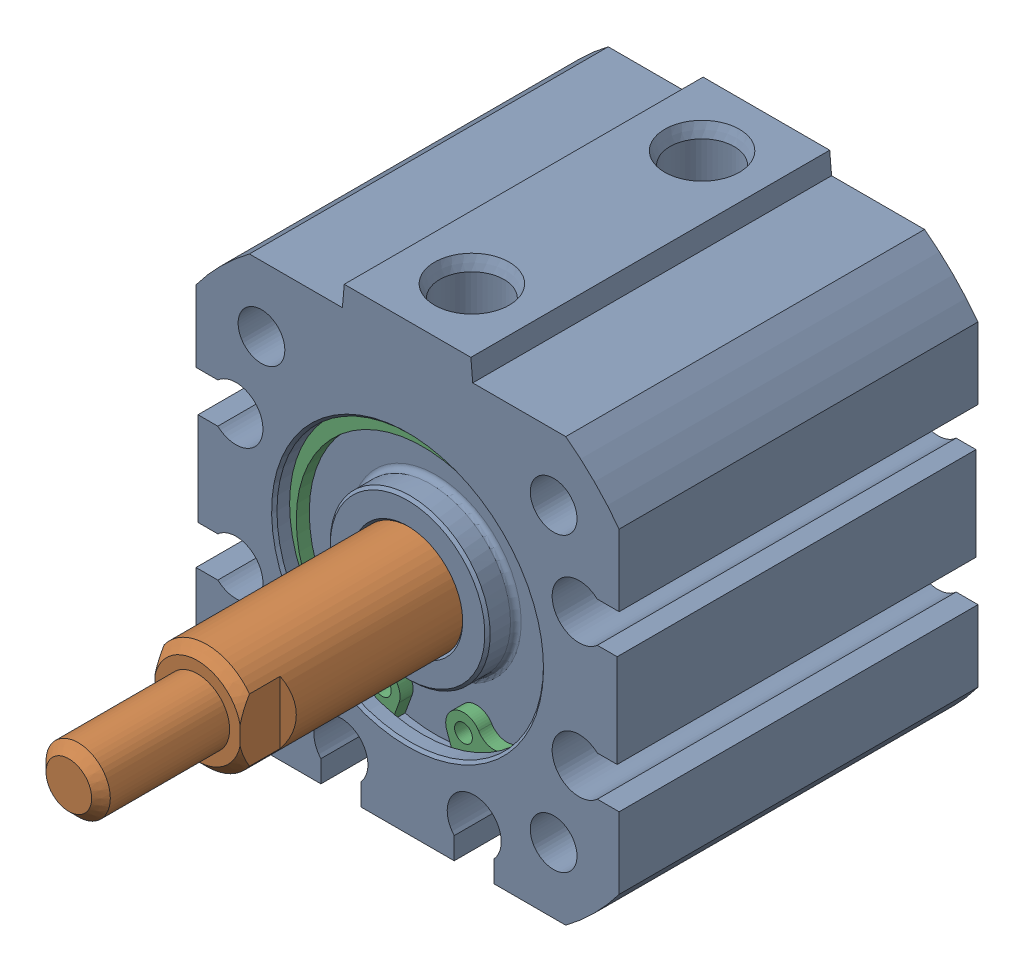
SolidWorks assembly 217-2778-001 Rev2_NCQ8A075-050M, configuration Default. Lengths in mm.
Overall size (31.75 33.34 52.34).
3 component instances, 3 part files, 0 mates.
Components (placement in the parent):
- 217-2778-NCQ8A075-050M_NCQ8 Tube_075A-1: 217-2778-NCQ8A075-050M_NCQ8 Tube_075A [Default] at origin size (31.75 33.34 26.92)
- 217-2778-NCQ8A075-050M_NCQ8 Rod_075M-1: 217-2778-NCQ8A075-050M_NCQ8 Rod_075M [Default] at (0 0 3.6101) x (-1 0 0) z (0 0 1) size (18.95 18.95 35.27)
- 217-2778-NCQ8A075-050M_Snap Ring_075-1: 217-2778-NCQ8A075-050M_Snap Ring_075 [Default] at (0 0 10.362) size (21 20.74 0.97)
